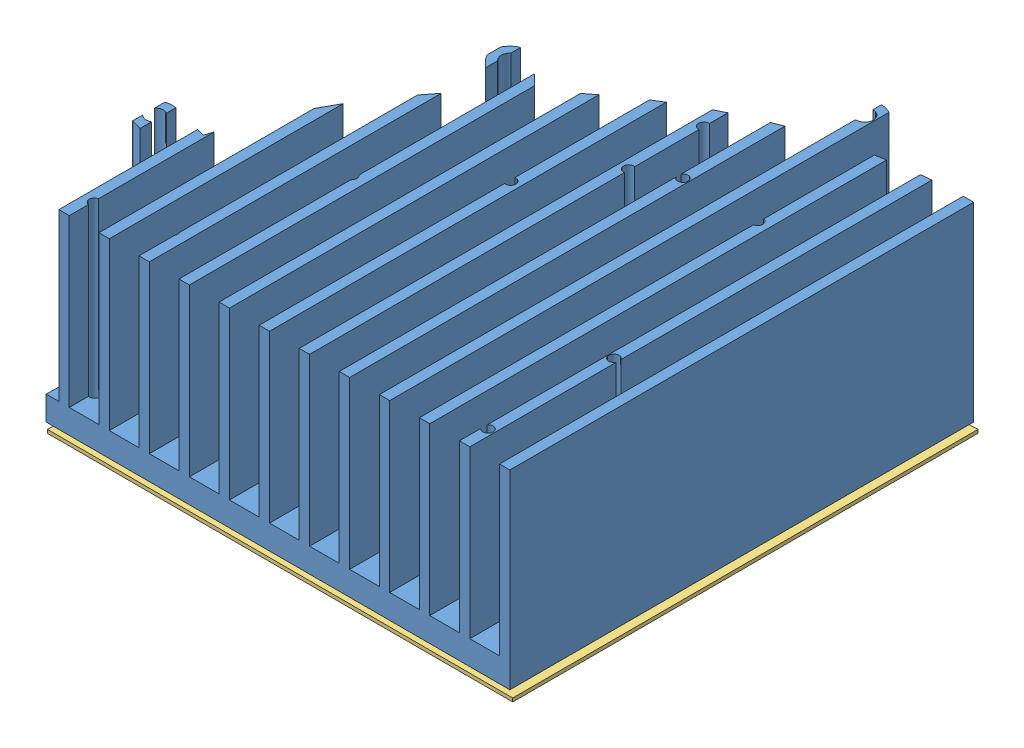
SolidWorks assembly pazargunu, configuration Default. Lengths in mm.
Overall size (145.52 58.56 145.06).
14 component instances, 4 part files, 8 mates.
Components (placement in the parent):
- Heat_sink_materialli-1: Heat_sink_materialli [Default] at (-49.1757 52.5764 -147.3718) size (145.06 55 145.06)
- thermal-iso-1: thermal-iso [Default] at (4.9608 50.5764 168.2161) x (0.999044 0 -0.043705) z (0.043705 0 0.999044) size (17 2 14)
- thermal-iso-5: thermal-iso [Default] at (12.7943 50.5764 141.7445) x (0.979558 0 0.201163) z (-0.201163 0 0.979558) size (17 2 14)
- thermal-iso-6: thermal-iso [Default] at (26.8452 50.5764 117.9809) x (0.90096 0 0.433901) z (-0.433901 0 0.90096) size (17 2 14)
- thermal-iso-7: thermal-iso [Default] at (46.2646 50.5764 98.3606) x (0.768002 0 0.640448) z (-0.640448 0 0.768002) size (17 2 14)
- thermal-iso-8: thermal-iso [Default] at (69.8819 50.5764 84.066) x (0.588697 0 0.808354) z (-0.808354 0 0.588697) size (17 2 14)
- thermal-iso-9: thermal-iso [Default] at (96.2716 50.5764 75.9602) x (0.373867 0 0.927482) z (-0.927482 0 0.373867) size (17 2 14)
- PCB-1: PCB [Default] at (-217.7167 49.5764 20.8462) x (0 0 -1) z (0 1 0) size (134.41 134.41 1)
- Gan-1: Gan [Default] at (-2.193 49.5764 168.5416) x (-0.999391 0 0.034899) z (0.034899 0 0.999391) size (8.5 0.56 7.1)
- Gan-2: Gan [Default] at (12.6343 49.0164 141.8764) x (0.981627 0 0.190809) z (-0.190809 0 0.981627) size (8.5 0.56 7.1)
- Gan-3: Gan [Default] at (26.9172 49.0164 118.2146) x (0.898794 0 0.438371) z (-0.438371 0 0.898794) size (8.5 0.56 7.1)
- Gan-4: Gan [Default] at (46.1114 49.0164 98.5328) x (0.766044 0 0.642788) z (-0.642788 0 0.766044) size (8.5 0.56 7.1)
- Gan-5: Gan [Default] at (69.863 49.0164 84.3016) x (0.573576 0 0.819152) z (-0.819152 0 0.573576) size (8.5 0.56 7.1)
- Gan-6: Gan [Default] at (96.1924 49.0164 76.3008) x (0.34202 0 0.939693) z (-0.939693 0 0.34202) size (8.5 0.56 7.1)
Mates (geometry in assembly coordinates):
- Coincident2: coincident anti-aligned: plane of Heat_sink_materialli-1 through (-49.1757 52.5764 852.6282) normal (0 -1 0); plane of thermal-iso-1 through (4.9608 52.5764 168.2161) normal (0 1 0)
- Coincident3: coincident anti-aligned: plane of thermal-iso-1 through (4.9608 50.5764 168.2161) normal (0 -1 0); plane of PCB-1 through (116.2833 50.5764 186.2546) normal (0 1 0)
- Coincident5: coincident anti-aligned: plane of PCB-1 through (116.2833 49.5764 186.2546) normal (0 -1 0); plane of Gan-1 through (-2.193 49.5764 168.5416) normal (0 1 0)
- Coincident8: coincident anti-aligned: plane of PCB-1 through (116.2833 49.5764 186.2546) normal (0 -1 0); plane of Gan-2 through (12.6343 49.5764 141.8764) normal (0 1 0)
- Coincident9: coincident anti-aligned: plane of PCB-1 through (116.2833 49.5764 186.2546) normal (0 -1 0); plane of Gan-3 through (26.9172 49.5764 118.2146) normal (0 1 0)
- Coincident10: coincident anti-aligned: plane of PCB-1 through (116.2833 49.5764 186.2546) normal (0 -1 0); plane of Gan-4 through (46.1114 49.5764 98.5328) normal (0 1 0)
- Coincident11: coincident anti-aligned: plane of PCB-1 through (116.2833 49.5764 186.2546) normal (0 -1 0); plane of Gan-5 through (69.863 49.5764 84.3016) normal (0 1 0)
- Coincident12: coincident anti-aligned: plane of PCB-1 through (116.2833 49.5764 186.2546) normal (0 -1 0); plane of Gan-6 through (96.1924 49.5764 76.3008) normal (0 1 0)
